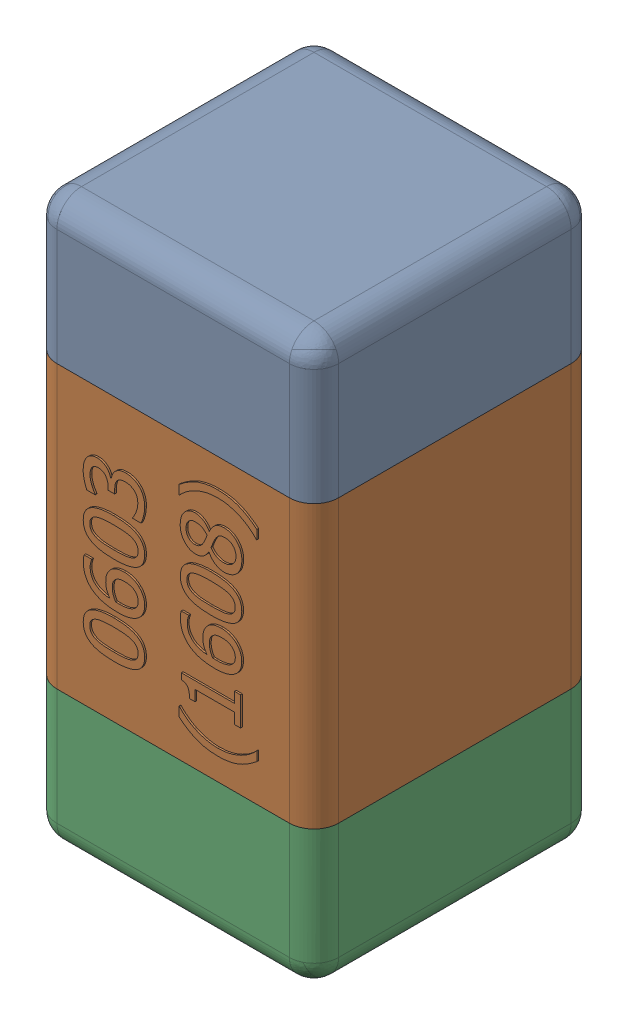
SolidWorks assembly C36, configuration Standard. Lengths in mm.
Overall size (0.81 1.61 0.81).
4 component instances, 3 part files, 0 mates.
Components (placement in the parent):
- C36-subassembly-1-1: C36-subassembly-1 [Standard] at (-14.4001 3.4001 0) x (0 1 0) z (0 0 1) size (1.61 0.81 0.81)
  - User Library-0603_Cap-1: User Library-0603_Cap [Standard] at origin size (0.41 0.81 0.81)
  - User Library-0603_Cap-1-1: User Library-0603_Cap-1 [Standard] at origin size (0.8 0.8 0.81)
  - User Library-0603_Cap-2-1: User Library-0603_Cap-2 [Standard] at origin size (0.41 0.81 0.81)
